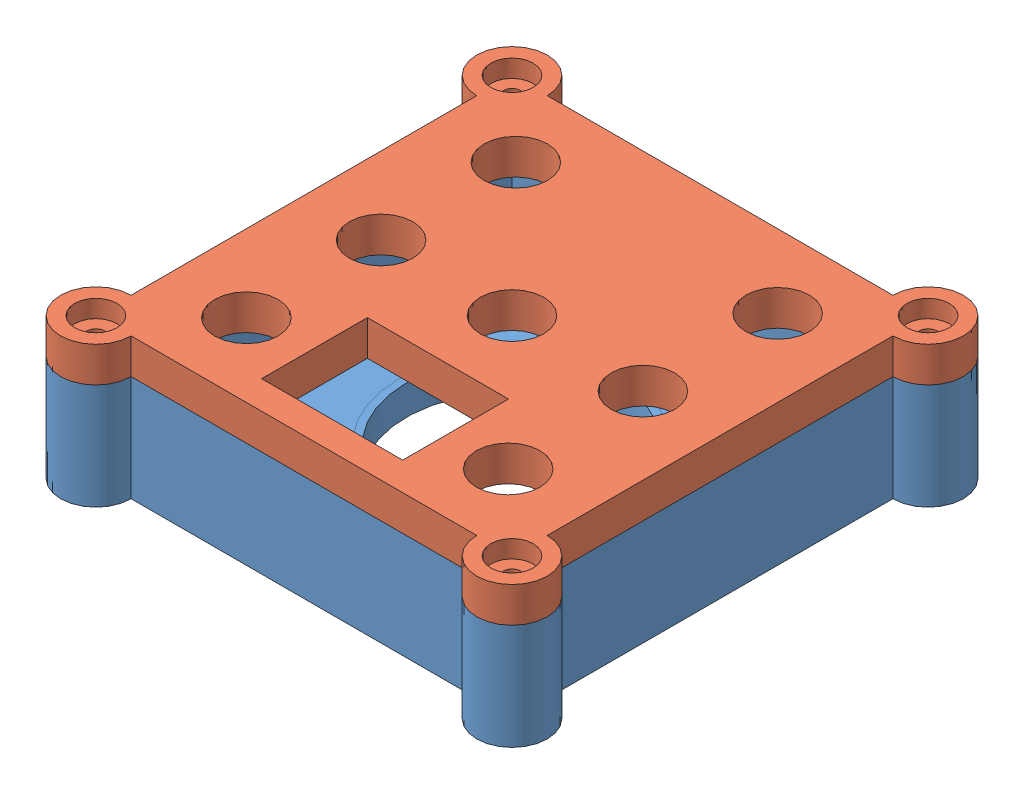
SolidWorks assembly Oblig1_Assembly, configuration Default. Lengths in mm.
Overall size (69 20 69).
2 component instances, 2 part files, 3 mates.
Components (placement in the parent):
- Oblig1box – V3 - skruer-1: Oblig1box – V3 - skruer [Default] at (42.3104 26.5084 45.5863) size (69 15 69)
- Oblig1lid -V4 - skruer-1: Oblig1lid -V4 - skruer [Default] at (42.3104 41.5084 45.5863) size (69 5 69)
Mates (geometry in assembly coordinates):
- Coincident3: coincident anti-aligned: plane of Oblig1box – V3 - skruer-1 through (42.3104 41.5084 45.5863) normal (0 1 0); plane of Oblig1lid -V4 - skruer-1 through (42.3104 41.5084 45.5863) normal (0 -1 0)
- Coincident4: coincident aligned: plane of Oblig1box – V3 - skruer-1 through (71.8104 41.5084 16.0863) normal (1 0 0); plane of Oblig1lid -V4 - skruer-1 through (71.8104 46.5084 16.0863) normal (1 0 0)
- Coincident5: coincident aligned: plane of Oblig1box – V3 - skruer-1 through (12.8104 41.5084 75.0863) normal (0 0 1); plane of Oblig1lid -V4 - skruer-1 through (12.8104 46.5084 75.0863) normal (0 0 1)
